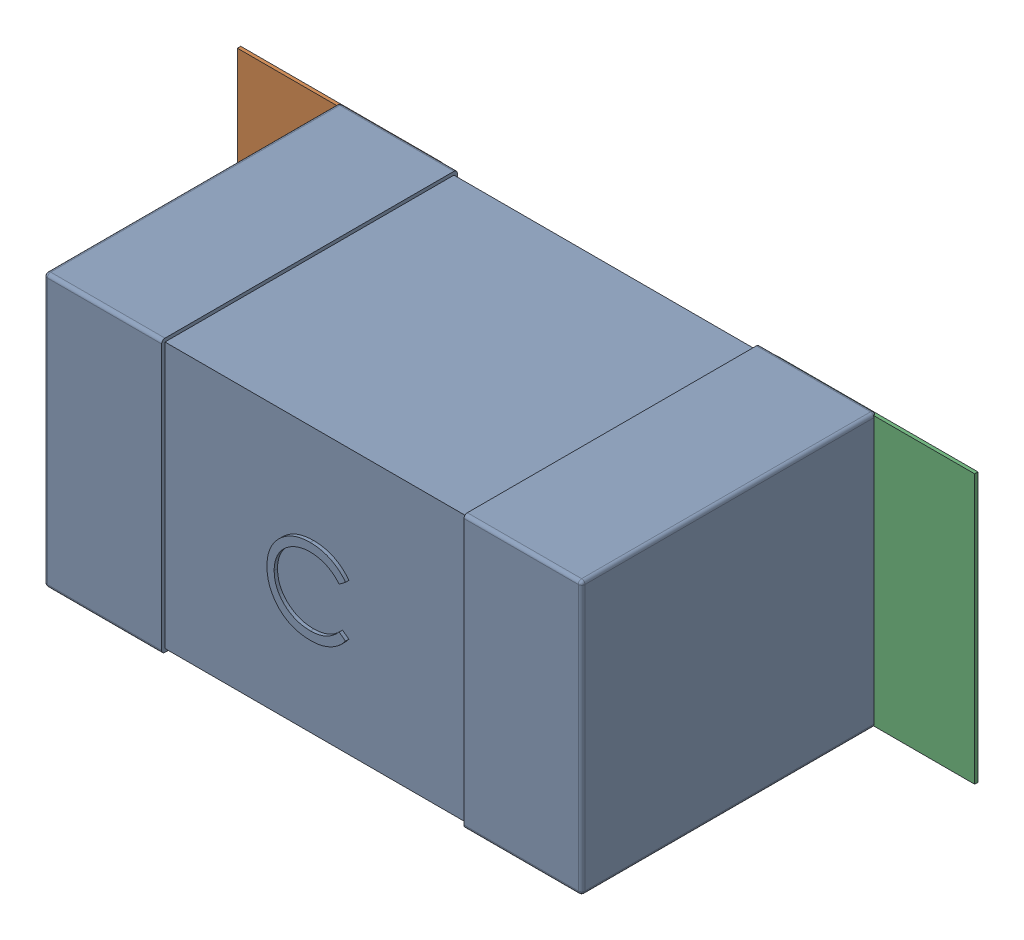
SolidWorks assembly C65, configuration Défaut. Lengths in mm.
Overall size (2.19 0.81 0.88).
5 component instances, 2 part files, 0 mates.
Components (placement in the parent):
- 0603_C-1: 0603_C [Défaut] at (41.0028 -13.716 0) x (1 0 0) z (0 0 1) size (1.6 0.81 0.88)
- 6634915696-1: 6634915696 [Défaut] at (40.6579 -13.716 0) size (0.6 0.8 0.01)
  - Extruded_497-1: Extruded_497 [Défaut] at origin size (0.6 0.8 0.01)
- 6634915696-2: 6634915696 [Défaut] at (42.2528 -13.716 0) size (0.6 0.8 0.01)
  - Extruded_497-1: Extruded_497 [Défaut] at origin size (0.6 0.8 0.01)
